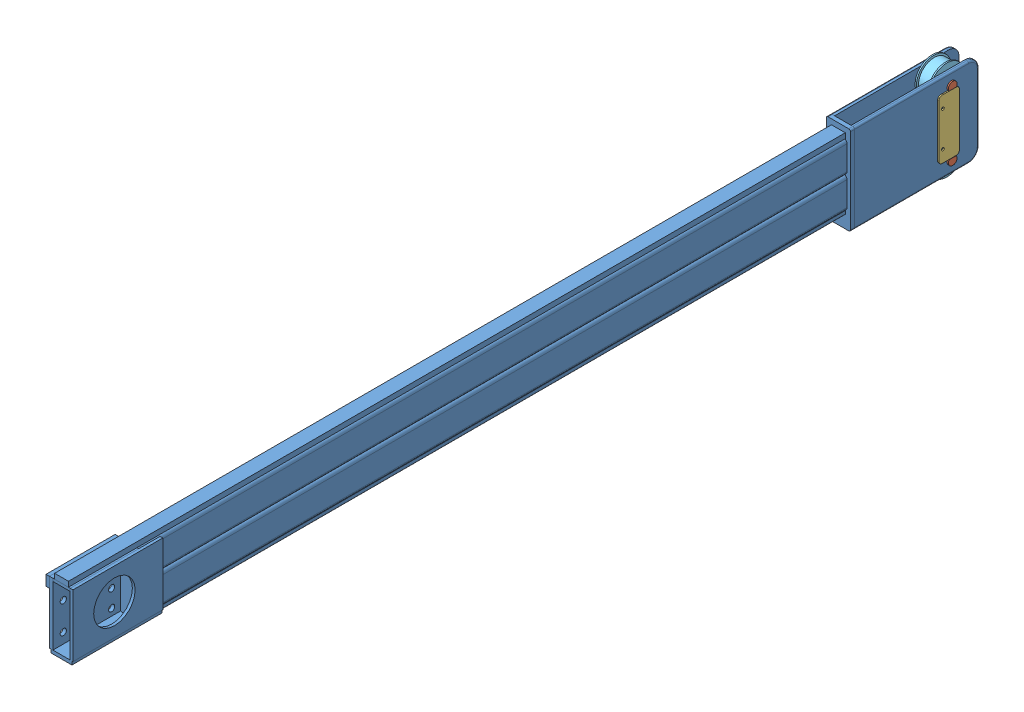
SolidWorks assembly 内臂装配, configuration 默认. Lengths in mm.
Overall size (84 306.26 2620).
12 component instances, 6 part files, 28 mates.
Components (placement in the parent):
- 内臂-1: 内臂 [默认<按加工>] at (10 -744.5927 -8) size (80 256 2620)
- 内壁轮轴-1: 内壁轮轴 [默认] at (-5 -1463.7961 -6.7179) x (1 0 0) z (0 -0.282313 0.959322) size (74 25 25)
- 内壁轮轴-2: 内壁轮轴 [默认] at (-5 -41.3892 -4693.2821) x (1 0 0) z (0 0.282313 -0.959322) size (74 25 25)
- 卡板-1: 卡板 [默认] at (60 -744.5927 -8) x (0 0 -1) z (1 0 0) size (60 171.5 3.5)
- deep groove ball bearings gb-1: deep groove ball bearings gb [Rolling bearings 16005 GB 276-94] at (11 -659.5927 -2350) x (1 0 0) z (0 0.338345 -0.941022) size (8 47 47)
- deep groove ball bearings gb-2: deep groove ball bearings gb [Rolling bearings 16005 GB 276-94] at (41 -659.5927 -2350) x (1 0 0) z (0 0.667042 0.74502) size (8 47 47)
- 内壁走轮-2: 内壁走轮 [默认] at (14.1076 -479.4912 -3341.8492) x (1 0 0) z (0 0.622739 0.78243) size (42 100 100)
- 内壁走轮-3: 内壁走轮 [默认] at (14.1076 -87.0126 -3013.8959) size (42 100 100)
- deep groove ball bearings gb-3: deep groove ball bearings gb [Rolling bearings 16005 GB 276-94] at (11 -845.5927 -2350) size (8 47 47)
- deep groove ball bearings gb-4: deep groove ball bearings gb [Rolling bearings 16005 GB 276-94] at (41 -845.5927 -2350) size (8 47 47)
- 轴套-2: 轴套 [默认] at (-337.1091 8.7998 -316.7739) size (4.5 32 32)
- 轴套-3: 轴套 [默认] at (-294.6091 8.7998 -316.7739) size (4.5 32 32)
Mates (geometry in assembly coordinates):
- 重合1: coincident: plane of 内臂-1 through (50 -664.5927 0) normal (0 0 1); plane of assembly through (0 0 0) normal (0 0 1)
- 重合3: coincident: plane of 内臂-1 through (0 -664.5927 -2058) normal (-1 0 0); plane of assembly through (0 0 0) normal (1 0 0)
- 同心1: concentric: cylinder of 内臂-1 through (95.3553 -659.5927 -2350) axis (-1 0 0) radius 12.5; cylinder of 内壁轮轴-1 through (64 -659.5927 -2350) axis (-1 0 0) radius 12.5
- 重合4: coincident: plane of 内臂-1 through (-10 -624.5927 -2430) normal (-1 0 0); plane of 内壁轮轴-1 through (-10 -659.5927 -2350) normal (-1 0 0)
- 同心2: concentric: cylinder of 内臂-1 through (95.3553 -845.5927 -2350) axis (-1 0 0) radius 12.5; cylinder of 内壁轮轴-2 through (64 -845.5927 -2350) axis (-1 0 0) radius 12.5
- 重合5: coincident: plane of 内臂-1 through (-10 -624.5927 -2430) normal (-1 0 0); plane of 内壁轮轴-2 through (-10 -845.5927 -2350) normal (-1 0 0)
- 在位1: in place: plane of ? through (65 -71.3688 -2540) normal (1 0 0); plane of ? through (65 0 0) normal (1 0 0); moOrthogonalPlaneRef_w of ? through (65 -71.3688 -2540) normal (1 0 0); plane of ? through (65 0 0) normal (0 1 0); plane of ? through (65 -71.3688 -2540) normal (1 0 0); plane of ? through (65 0 0) normal (0 0 -1); plane of 内臂-1 through (60 -880.5927 -2430) normal (1 0 0); unknown of 卡板-1
- 重合6: coincident: plane of 内臂-1; plane of 卡板-1
- 重合7: coincident: moOrthogonalPlaneRef_w of 内臂-1 through (60 -744.5927 -8) normal (0 1 0); plane of 卡板-1 through (60 -744.5927 -8) normal (0 1 0)
- 重合8: coincident: moOrthogonalPlaneRef_w of 内臂-1 through (60 -744.5927 -8) normal (0 0 1); plane of 卡板-1 through (60 -744.5927 -8) normal (0 0 -1)
- 平行1: parallel: plane of 内壁轮轴-1 through (64 -666.5927 -2360.3562) normal (0 -1 0); plane of 卡板-1 through (63.5 -666.8427 -2310) normal (0 1 0)
- 平行2: parallel: plane of 内壁轮轴-2 through (64 -838.5927 -2339.6438) normal (0 1 0); plane of 卡板-1 through (63.5 -838.3427 -2310) normal (0 -1 0)
- 同心6: concentric: cylinder of 内壁轮轴-1 through (64 -659.5927 -2350) axis (-1 0 0) radius 12.5; cylinder of deep groove ball bearings gb-1 through (4.0286 -659.5927 -2350) axis (-1 0 0) radius 12.5
- 距离2: distance = 3 mm: plane of 内壁走轮-2 through (47 -682.8661 -2353.2554) normal (1 0 0); plane of 内臂-1 through (50 -880.5927 -2430) normal (-1 0 0)
- 同心8: concentric: cylinder of deep groove ball bearings gb-1 through (2.2893 -659.5927 -2350) axis (-1 0 0) radius 23.5; cylinder of 内壁走轮-2 through (58.0107 -659.5927 -2350) axis (1 0 0) radius 23.5
- 重合15: coincident: plane of deep groove ball bearings gb-2 through (37 -642.0847 -2365.6755) normal (-1 0 0); plane of 内壁走轮-2 through (37 -682.8661 -2353.2554) normal (1 0 0)
- 同心9: concentric: cylinder of deep groove ball bearings gb-2 through (32.2893 -659.5927 -2350) axis (-1 0 0) radius 23.5; cylinder of 内壁走轮-2 through (58.0107 -659.5927 -2350) axis (1 0 0) radius 23.5
- 重合17: coincident: plane of deep groove ball bearings gb-1 through (15 -681.7067 -2357.9511) normal (1 0 0); plane of 内壁走轮-2 through (15 -679.3998 -2352.7705) normal (-1 0 0)
- 重合18: coincident: plane of 内壁走轮-3 through (37 -861.7752 -2367.0404) normal (1 0 0); plane of deep groove ball bearings gb-4 through (37 -822.0927 -2350) normal (-1 0 0)
- 同心10: concentric: cylinder of 内壁走轮-3 through (58.0107 -845.5927 -2350) axis (1 0 0) radius 23.5; cylinder of deep groove ball bearings gb-4 through (32.2893 -845.5927 -2350) axis (-1 0 0) radius 23.5
- 重合19: coincident: plane of 内壁走轮-3 through (15 -859.3651 -2364.5025) normal (-1 0 0); plane of deep groove ball bearings gb-3 through (15 -822.0927 -2350) normal (1 0 0)
- 同心11: concentric: cylinder of 内壁走轮-3 through (58.0107 -845.5927 -2350) axis (1 0 0) radius 23.5; cylinder of deep groove ball bearings gb-3 through (2.2893 -845.5927 -2350) axis (-1 0 0) radius 23.5
- 同心12: concentric: cylinder of 内壁轮轴-2 through (64 -845.5927 -2350) axis (-1 0 0) radius 12.5; cylinder of deep groove ball bearings gb-3 through (4.0286 -845.5927 -2350) axis (-1 0 0) radius 12.5
- 距离3: distance = 3 mm: plane of 内壁走轮-3 through (47 -861.7752 -2367.0404) normal (1 0 0); plane of 内臂-1 through (50 -880.5927 -2430) normal (-1 0 0)
- 重合24: coincident: plane of deep groove ball bearings gb-4 through (45 -833.0927 -2350) normal (1 0 0); plane of 轴套-3 through (45 -649.2849 -2342.0785) normal (-1 0 0)
- 同心15: concentric: cylinder of 内壁轮轴-1 through (64 -659.5927 -2350) axis (-1 0 0) radius 12.5; cylinder of 轴套-3 through (43.9375 -659.5927 -2350) axis (-1 0 0) radius 13
- 同心16: concentric: cylinder of 内壁轮轴-1 through (64 -659.5927 -2350) axis (-1 0 0) radius 12.5; cylinder of 轴套-2 through (1.4375 -659.5927 -2350) axis (-1 0 0) radius 13
- 重合25: coincident: plane of deep groove ball bearings gb-1 through (7 -674.8058 -2355.4699) normal (-1 0 0); plane of 轴套-2 through (7 -649.2849 -2342.0785) normal (1 0 0)
